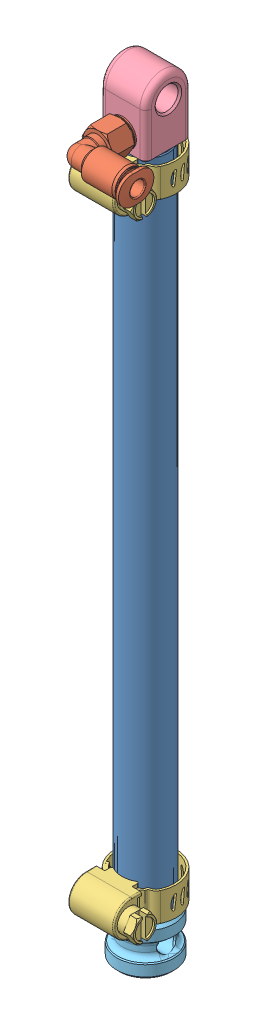
SolidWorks assembly AARL_QR_PN_PA_BR_KN_EX-Extensor, configuration Default. Lengths in mm.
Overall size (24.22 215.9 31.28).
6 component instances, 5 part files, 15 mates.
Components (placement in the parent):
- AARL_QR_PN_PA_BR_KN_EX_001-1: AARL_QR_PN_PA_BR_KN_EX_001 [Resting] at origin size (12.7 184.15 12.7)
- AARL_Puppy_18_02_57_010-QSML-M3-4-1: AARL_Puppy_18_02_57_010-QSML-M3-4 [Default] at (0 96.8375 17.85) x (1 0 0) z (0 0 -1) size (20.32 8 18.9)
- AARL_Puppy_18_02_57_011-5388K140_Hose-Clamp-1: AARL_Puppy_18_02_57_011-5388K140_Hose-Clamp [5388K14] at (0 -87.122 0) x (1 0 0) z (0 -1 0) size (19.43 23.71 9.91)
- AARL_Puppy_18_02_57_011-5388K140_Hose-Clamp-2: AARL_Puppy_18_02_57_011-5388K140_Hose-Clamp [5388K14] at (0 87.122 0) x (1 0 0) z (0 -1 0) size (19.43 23.71 9.91)
- AARL_QR_PN_EP_001-1: AARL_QR_PN_EP_001 [Default] at (0 104.775 0) x (0 0 1) z (-1 0 0) size (12.7 31.75 12.7)
- AARL_QR_PN_EP_002-1: AARL_QR_PN_EP_002 [Default] at (0 -92.075 0) x (-1 0 0) z (0 0 1) size (15.88 25.4 15.88)
Mates (geometry in assembly coordinates):
- Concentric1: concentric aligned: cylinder of AARL_QR_PN_PA_BR_KN_EX_001-1 through (0 11.6086 0) axis (0 1 0) radius 4.7625; cylinder of AARL_QR_PN_EP_001-1 through (0 114.319 0) axis (0 1 0) radius 4.3656
- Coincident1: coincident anti-aligned: plane of AARL_QR_PN_PA_BR_KN_EX_001-1 through (4.7625 92.075 0) normal (0 1 0); plane of AARL_QR_PN_EP_001-1 through (-6.35 92.075 -6.35) normal (0 -1 0)
- Parallel1: parallel aligned: plane of AARL_QR_PN_EP_001-1 through (-6.35 92.075 6.35) normal (0 0 1)
- Concentric2: concentric aligned: cylinder of AARL_Puppy_18_02_57_010-QSML-M3-4-1 through (0 96.8375 6.35) axis (0 0 1) radius 1.5; cylinder of AARL_QR_PN_EP_001-1 through (0 96.8375 6.35) axis (0 0 1) radius 2.0193
- Coincident3: coincident anti-aligned: plane of AARL_Puppy_18_02_57_010-QSML-M3-4-1 through (0 96.8375 6.35) normal (0 0 -1); plane of AARL_QR_PN_EP_001-1 through (-6.35 92.075 6.35) normal (0 0 1)
- Parallel2: parallel anti-aligned: plane of AARL_Puppy_18_02_57_010-QSML-M3-4-1 through (-2.3094 100.8375 13.4056) normal (0 1 0); plane of AARL_QR_PN_EP_001-1 through (-6.35 92.075 -6.35) normal (0 -1 0)
- Concentric4: concentric anti-aligned: cylinder of AARL_QR_PN_PA_BR_KN_EX_001-1 through (0 11.6086 0) axis (0 1 0) radius 4.7625; cylinder of AARL_QR_PN_EP_002-1 through (0 -99.8127 0) axis (0 -1 0) radius 4.3656
- Coincident5: coincident anti-aligned: plane of AARL_QR_PN_PA_BR_KN_EX_001-1 through (6.35 -92.075 0) normal (0 -1 0); plane of AARL_QR_PN_EP_002-1 through (-4.3656 -92.075 0) normal (0 1 0)
- Parallel3: parallel anti-aligned: cylinder of AARL_QR_PN_EP_001-1 through (-6.35 104.775 0) axis (1 0 0) radius 3.175; cylinder of AARL_QR_PN_EP_002-1 through (7.9375 -98.425 0) axis (-1 0 0) radius 2.3813
- Concentric6: concentric aligned: cylinder of AARL_QR_PN_PA_BR_KN_EX_001-1 through (0 11.6086 0) axis (0 1 0) radius 6.35; cylinder of AARL_Puppy_18_02_57_011-5388K140_Hose-Clamp-2 through (0 83.1532 0) axis (0 1 0) radius 7.9375
- Coincident6: coincident aligned: plane of AARL_Puppy_18_02_57_011-5388K140_Hose-Clamp-2 through (6.35 87.122 10.2337) normal (1 0 0); plane of AARL_QR_PN_EP_001-1 through (6.35 104.775 0) normal (1 0 0)
- Coincident7: coincident anti-aligned: plane of AARL_Puppy_18_02_57_011-5388K140_Hose-Clamp-2 through (0 92.075 0) normal (0 1 0); plane of AARL_QR_PN_EP_001-1 through (-6.35 92.075 -6.35) normal (0 -1 0)
- Concentric7: concentric aligned: cylinder of AARL_QR_PN_PA_BR_KN_EX_001-1 through (0 11.6086 0) axis (0 1 0) radius 6.35; cylinder of AARL_Puppy_18_02_57_011-5388K140_Hose-Clamp-1 through (0 -91.0907 0) axis (0 1 0) radius 7.9375
- Coincident8: coincident aligned: plane of AARL_Puppy_18_02_57_011-5388K140_Hose-Clamp-1 through (6.35 -87.122 10.2337) normal (1 0 0); plane of AARL_Puppy_18_02_57_011-5388K140_Hose-Clamp-2 through (6.35 87.122 10.2337) normal (1 0 0)
- Coincident9: coincident: plane of AARL_Puppy_18_02_57_011-5388K140_Hose-Clamp-1 through (0 -92.075 0) normal (0 -1 0); plane of AARL_QR_PN_EP_002-1 through (-4.3656 -92.075 0) normal (0 1 0)
